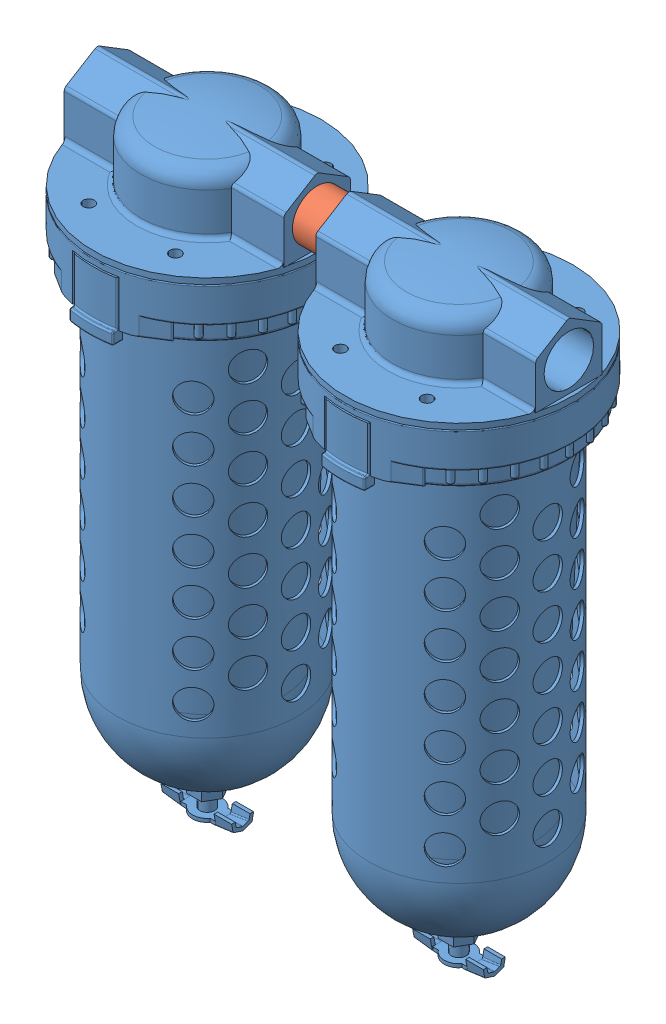
SolidWorks assembly ReadingTech_3P-060-P04-DCP, configuration Default. Lengths in mm.
Overall size (206.63 262.52 99.95).
3 component instances, 2 part files, 3 mates.
Components (placement in the parent):
- ReadingTech_3P-060-P04-P-1: ReadingTech_3P-060-P04-P [Default] at (-13.6833 -79.3072 -7.9101) size (98.17 262.52 99.95)
- ReadingTech_3P-060-P04-P-2: ReadingTech_3P-060-P04-P [Default] at (94.7747 -79.3072 -7.9101) size (98.17 262.52 99.95)
- ReadingTech- 60cfm_connector_.5in-1: ReadingTech- 60cfm_connector_.5in [Default] at (47.4037 136.5928 -7.9101) x (0 1 0) z (0 0 1) size (21.34 13.72 21.34)
Mates (geometry in assembly coordinates):
- Coincident1: coincident anti-aligned: circle of ReadingTech_3P-060-P04-P-1; circle of ReadingTech- 60cfm_connector_.5in-1
- Coincident2: coincident aligned: circle of ReadingTech_3P-060-P04-P-2; circle of ReadingTech- 60cfm_connector_.5in-1
- Coincident3: coincident aligned: plane of ReadingTech_3P-060-P04-P-1 through (33.6877 123.8928 6.3774) normal (0 0 1); plane of ReadingTech_3P-060-P04-P-2 through (142.1457 123.8928 6.3774) normal (0 0 1)
